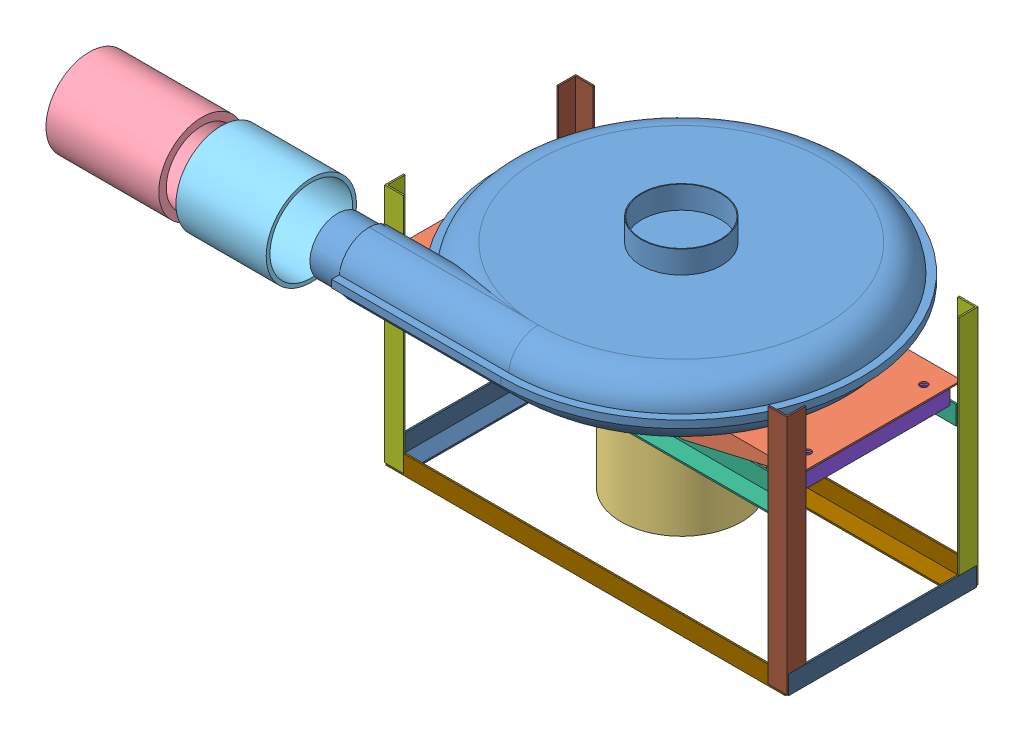
SolidWorks assembly ВытяжкаСБ, configuration По умолчанию. Lengths in mm.
Overall size (862.88 370.43 516.43).
19 component instances, 11 part files, 3 mates.
Components (placement in the parent):
- Вытяжка-1: Вытяжка [По умолчанию] at (105 197 361.5885) x (1 0 0) z (0 0 -1) size (860.38 326.43 516.43)
  - Улитка-1: Улитка [По умолчанию] at origin size (505 110.1 480)
  - Крепление-1: Крепление [По умолчанию] at (-265 45 2.5) size (530 38.5 215)
  - Мотор-1: Мотор [По умолчанию] at (0 247 0) x (-0.825077 0 -0.56502) z (-0.56502 0 0.825077) size (200 200 200)
  - Асбестовая-1: Асбестовая [По умолчанию] at (-595.3778 5 -192) x (0 -0.991749 -0.128194) z (0 -0.128194 0.991749) size (115 150 115)
  - Гофра-1: Гофра [По умолчанию] at (-420.0302 5 -192) x (0 -0.774417 -0.632675) z (0 -0.632675 0.774417) size (120 120 120)
- СбПодставка-1: СбПодставка [По умолчанию] at (354.5 103 981.1147) x (0 0 -1) z (-1 0 0) size (254 322 535)
  - ВПбоковина-1: ВПбоковина [По умолчанию] at (719.5262 0 515) x (0 0 -1) z (-1 0 0) size (531 25 25)
  - ВПбоковина-2: ВПбоковина [По умолчанию] at (519.5262 0 -16) x (0 0 1) z (1 0 0) size (531 25 25)
  - ВПребро-3: ВПребро [По умолчанию] at (492.5262 -125 517) x (0 1 0) z (-1 0 0) size (320 25 25)
  - ВПребро-4: ВПребро [По умолчанию] at (746.5262 -125 -18) x (0 1 0) z (1 0 0) size (320 25 25)
  - ВПтылАЛТ-1: ВПтылАЛТ [По умолчанию] at (519.5262 -45 -8) x (1 0 0) z (0 -1 0) size (200 25 25)
  - ВПтылАЛТ-2: ВПтылАЛТ [По умолчанию] at (719.5262 -45 507) x (-1 0 0) z (0 -1 0) size (200 25 25)
  - ВПбоковинаН-1: ВПбоковинаН [По умолчанию] at (492.5262 197 -16) x (0 0 1) z (0 1 0) size (531 25 25)
  - ВПбоковинаН-2: ВПбоковинаН [По умолчанию] at (746.5262 197 515) x (0 0 -1) z (0 1 0) size (531 25 25)
  - ВПтылН-1: ВПтылН [По умолчанию] at (744.5262 197 -18) x (-1 0 0) z (0 1 0) size (250 25 25)
  - ВПтылН-2: ВПтылН [По умолчанию] at (494.5262 197 517) x (1 0 0) z (0 1 0) size (250 25 25)
  - ВПребро2-1: ВПребро2 [По умолчанию] at (746.5262 -125 517) x (0 1 0) z (0 0 1) size (320 25 25)
  - ВПребро2-2: ВПребро2 [По умолчанию] at (492.5262 -125 -18) x (0 1 0) z (0 0 -1) size (320 25 25)
Mates (geometry in assembly coordinates):
- Концентричный1: concentric anti-aligned: cylinder of Вытяжка-1/Крепление-1 through (-140 152 284.0885) axis (0 -1 0) radius 5; cylinder of СбПодставка-1/ВПтылАЛТ-2 through (-140 123 284.0885) axis (0 1 0) radius 5
- Расстояние1: distance = 2 mm anti-aligned: plane of СбПодставка-1/ВПтылАЛТ-2 through (-127.5 148 461.5885) normal (0 1 0); plane of Вытяжка-1/Крепление-1 through (370 150 254.0885) normal (0 -1 0)
- Параллельность1: parallel aligned: plane of Вытяжка-1/Крепление-1 through (-160 152 359.0885) normal (-1 0 0); plane of СбПодставка-1/ВПтылАЛТ-2 through (-152.5 148 461.5885) normal (-1 0 0)
